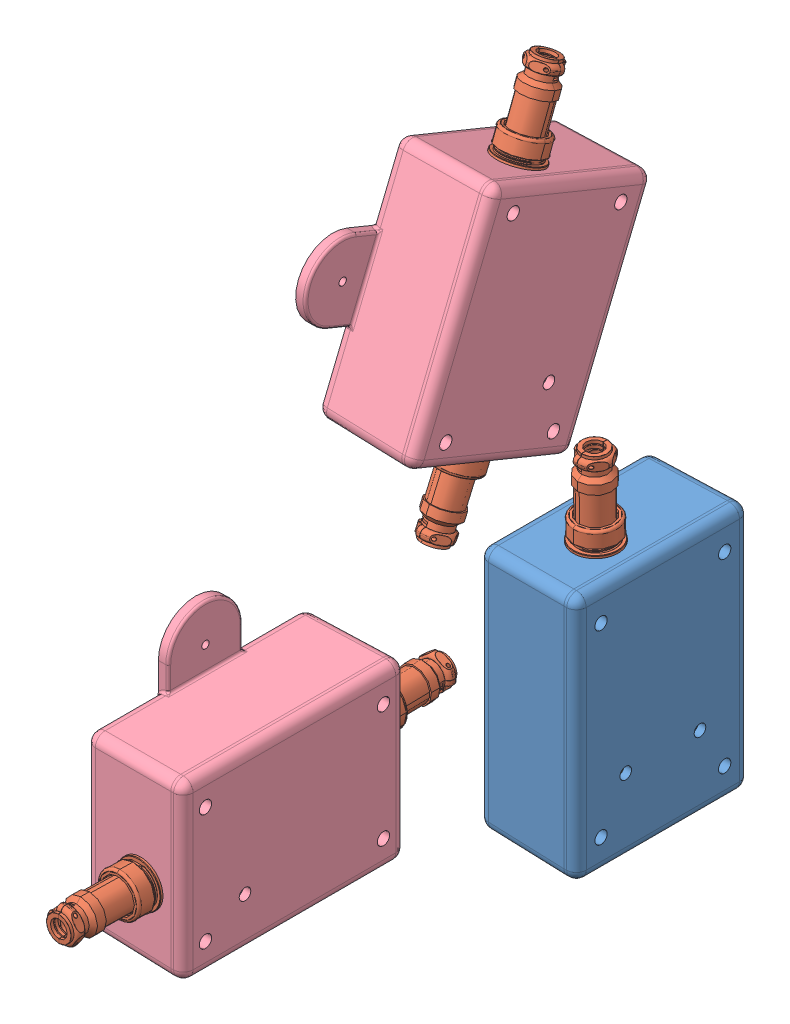
SolidWorks assembly Assem2, configuration Default. Lengths in mm.
Overall size (35.01 276.27 234.96).
14 component instances, 5 part files, 2 mates.
Components (placement in the parent):
- Base_Assem-1: Base_Assem [Default] at (3.2842 0.0119 12.0382) size (35.01 105.98 70)
  - Main_Controller-1: Main_Controller [Default] at (40.9971 40.6897 82.6321) size (40 100 70)
  - GX16-4P v2.step-1: GX16-4P v2.step [Default] at (27.8263 123.1648 92.1116) x (0.017452 -0.999848 0) z (0.035766 0.000624 -0.99936) size (47.5 21.45 18.91)
  - MCU_PCB.step-1: MCU_PCB.step [Default] at (15.4346 -29.3104 38.205) x (0 0.999999 0.001404) z (1 0 0) size (75.68 37.85 14.81)
- Module_Assem-1: Module_Assem [Default] at (-13.8669 277.5067 47.7158) x (1 0 0) z (0 -0.925535 0.378663) size (35.01 118.85 101.97)
  - Module-1: Module [Default] at (58.1482 61.5557 111.8773) size (40 118.85 90)
  - Sensor_PCB.step-1: Sensor_PCB.step [Default] at (32.5857 18.0107 158.8326) x (0 -0.001154 -0.999999) z (1 0 0) size (46.6 38.61 15.7)
  - GX16-4P v2.step-1: GX16-4P v2.step [Default] at (45.3324 54.2793 189.3585) x (0.017452 0 -0.999848) z (-0.023825 0.999716 -0.000416) size (47.5 21.45 18.91)
  - GX16-4P v2.step-2: GX16-4P v2.step [Default] at (46.1678 68.8229 34.3814) x (0.017452 0 0.999848) z (0.995324 0.095017 -0.017373) size (47.5 21.45 18.91)
- Module_Assem-2: Module_Assem [Default] at (-13.8669 8.734 131.7681) size (35.01 118.85 101.97)
  - Module-1: Module [Default] at (58.1482 61.5557 111.8773) size (40 118.85 90)
  - Sensor_PCB.step-1: Sensor_PCB.step [Default] at (32.5857 18.0107 158.8326) x (0 -0.001154 -0.999999) z (1 0 0) size (46.6 38.61 15.7)
  - GX16-4P v2.step-1: GX16-4P v2.step [Default] at (45.3324 54.2793 189.3585) x (0.017452 0 -0.999848) z (-0.023825 0.999716 -0.000416) size (47.5 21.45 18.91)
  - GX16-4P v2.step-2: GX16-4P v2.step [Default] at (46.1678 68.8229 34.3814) x (0.017452 0 0.999848) z (0.995324 0.095017 -0.017373) size (47.5 21.45 18.91)
Mates (geometry in assembly coordinates):
- Coincident1: coincident aligned: plane of Base_Assem-1/Main_Controller-1 through (9.2813 40.7016 94.6702) normal (-1 0 0); plane of Module_Assem-1/Module-1 through (9.2813 197.2693 147.0515) normal (-1 0 0)
- Coincident2: coincident aligned: plane of Base_Assem-1/Main_Controller-1 through (9.2813 40.7016 94.6702) normal (-1 0 0); plane of Module_Assem-2/Module-1 through (9.2813 70.2897 243.6454) normal (-1 0 0)
